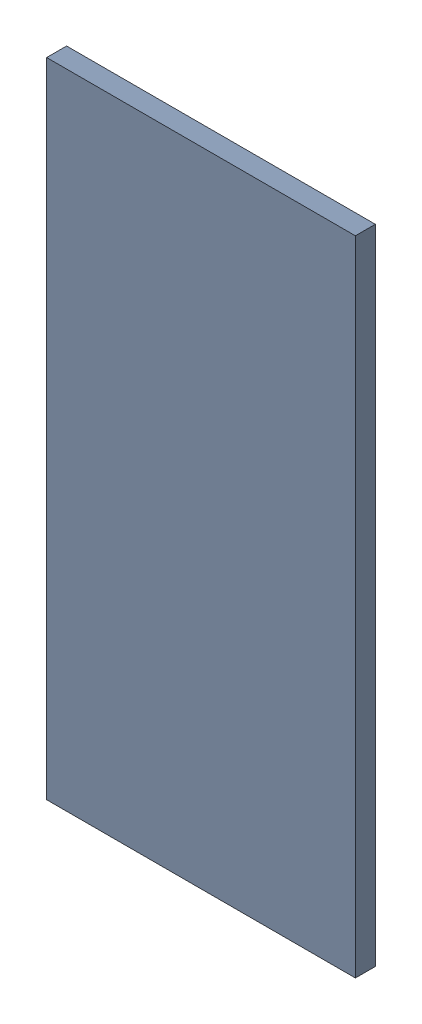
SolidWorks assembly Pad ADXL345-5(19.8mm,58.097mm) on Top Layer, configuration Predeterminado. Lengths in mm.
Overall size (0.55 1.15 0.04).
2 component instances, 1 part files, 0 mates.
Components (placement in the parent):
- Pad ADXL345-5(19.8mm,58.097mm) on Top Layer-1-1: Pad ADXL345-5(19.8mm,58.097mm) on Top Layer-1 [Predeterminado] at (-68.317 -44.187 -0.0457) size (0.55 1.15 0.04)
  - Pad ADXL345-5(19.8mm,58.097mm) on Top Layer-Part-1-1: Pad ADXL345-5(19.8mm,58.097mm) on Top Layer-Part-1 [Predeterminado] at origin size (0.55 1.15 0.04)
